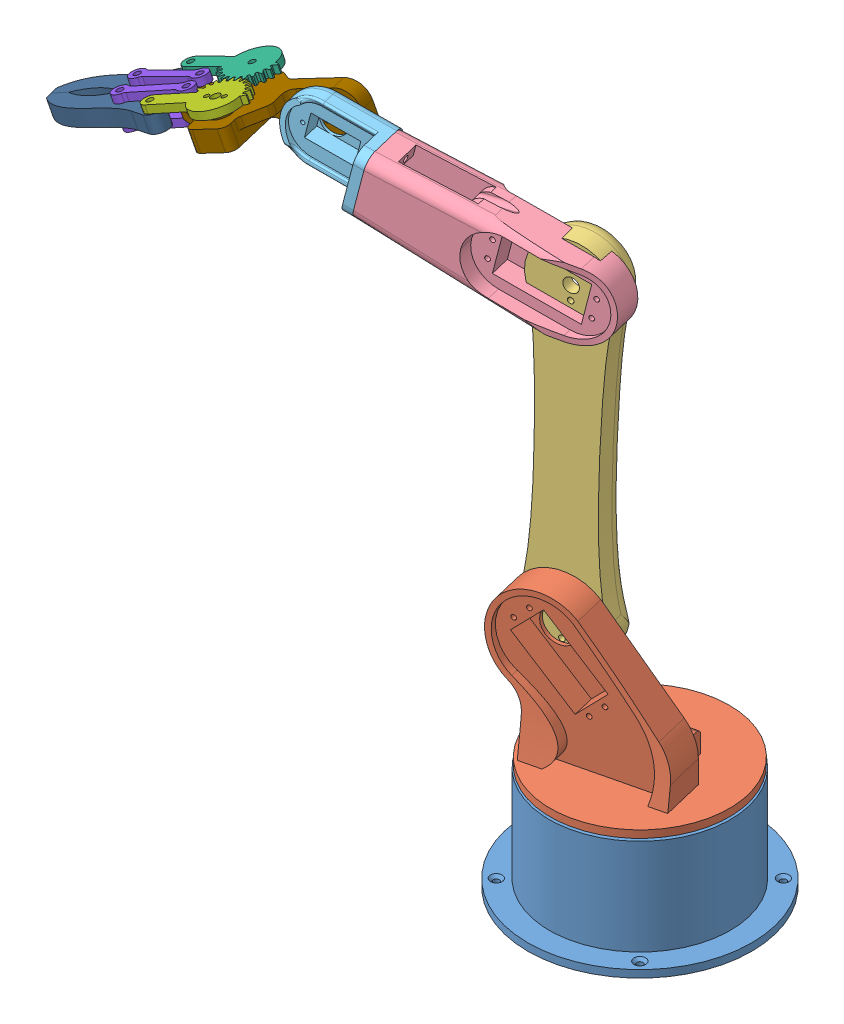
SolidWorks assembly Robotic Arm, configuration Default. Lengths in mm.
Overall size (333.86 325.62 149.88).
15 component instances, 10 part files, 15 mates.
Components (placement in the parent):
- Base-1: Base [Default] at (40.7793 36.1076 92.8796) size (121.25 56 121.25)
- Waist-1: Waist [Default] at (40.7793 93.1076 92.8796) x (-0.233849 0 -0.972273) z (0.972273 0 -0.233849) size (97 81.79 105.4)
- Arm 01-1: Arm 01 [Default] at (10.2173 150.3969 104.3443) x (-0.971972 0.024864 0.233776) z (-0.233849 0 -0.972273) size (58.02 214.69 21.06)
- Arm 02 v3-1: Arm 02 v3 [Default] at (-20.2557 318.087 105.5025) x (0.216544 0.974883 -0.052083) z (0.233849 0 0.972273) size (38.57 115 28.32)
- Arm 03-1: Arm 03 [Default] at (-71.2183 330.3365 122.9025) x (0.216544 0.974883 -0.052083) z (0.233849 0 0.972273) size (33 46 28)
- Gripper Assembly-2: Gripper Assembly [Default] at (-85.5006 347.4318 120.1943) x (0.233849 0 0.972273) z (-0.903375 -0.369736 0.217277) size (65.56 35.5 144.98)
  - gear1-1: gear1 [Default] at (-17.5467 12.6028 65.1565) x (-0.051418 0 0.998677) z (-0.998677 0 -0.051418) size (49.29 4 26.63)
  - gear2-1: gear2 [Default] at (10.7105 12.6028 44.992) x (0.082871 0 -0.99656) z (0.99656 0 0.082871) size (49.02 4 26.63)
  - grip link 1-1: grip link 1 [Default] at (-10.0646 0.1028 106.0462) x (0.033468 0 -0.99944) z (0.99944 0 0.033468) size (39 4 8)
  - Gripper base-1: Gripper base [Default] at (-22.027 4.1028 80.0636) size (44.4 28 77)
  - grip link 1-2: grip link 1 [Default] at (2.7155 0.1028 106.0146) x (-0.056211 0 -0.998419) z (0.998419 0 -0.056211) size (39 4 8)
  - Gripper 1-1: Gripper 1 [Default] at (8.7088 4.1028 79.2175) x (0 1 0) z (0.392312 0 -0.919832) size (8.5 22.22 65.31)
  - Gripper 1-2: Gripper 1 [Default] at (-15.9423 12.6028 79.2236) x (0 -1 0) z (-0.388345 0 -0.921514) size (8.5 22.22 65.31)
  - grip link 1-3: grip link 1 [Default] at (2.7155 12.6028 106.0146) x (-0.056211 0 -0.998419) z (0.998419 0 -0.056211) size (39 4 8)
  - grip link 1-4: grip link 1 [Default] at (-10.0646 16.6028 106.0462) x (0.033468 0 -0.99944) z (-0.99944 0 -0.033468) size (39 4 8)
Mates (geometry in assembly coordinates):
- Concentric5: concentric aligned: cylinder of Base-1 through (40.7793 92.1076 92.8796) axis (0 -1 0) radius 49; cylinder of Waist-1 through (40.7793 97.1076 92.8796) axis (0 -1 0) radius 48.5
- Distance1: distance = 1 mm anti-aligned: plane of Base-1 through (40.7793 92.1076 92.8796) normal (0 1 0); plane of Waist-1 through (40.7793 93.1076 92.8796) normal (0 -1 0)
- Parallel10: parallel anti-aligned: plane of Arm 02 v3-1 through (-72.3875 330.3365 118.0411) normal (-0.947852 0.222719 0.227975); plane of Arm 03-1 through (-71.2183 330.3365 122.9025) normal (0.947852 -0.222719 -0.227975)
- Parallel11: parallel aligned: line of Arm 02 v3-1 through (-71.986 340.5667 109.7164) axis (-0.216544 -0.974883 0.052083); line of Arm 03-1 through (-72.2185 340.5728 108.7438) axis (-0.216544 -0.974883 0.052083)
- Concentric21: concentric anti-aligned: cylinder of Arm 02 v3-1 through (-58.5912 341.7577 120.3797) axis (-0.947852 0.222719 0.227975) radius 1.5; cylinder of Arm 03-1 through (-111.6709 354.23 133.1463) axis (0.947852 -0.222719 -0.227975) radius 1.5
- Coincident57: coincident anti-aligned: plane of Arm 02 v3-1 through (-72.3875 330.3365 118.0411) normal (-0.947852 0.222719 0.227975); plane of Arm 03-1 through (-71.2183 330.3365 122.9025) normal (0.947852 -0.222719 -0.227975)
- Concentric24: concentric anti-aligned: cylinder of Arm 02 v3-1 through (-64.6545 314.461 121.838) axis (-0.947852 0.222719 0.227975) radius 1.5; cylinder of Arm 03-1 through (-117.7342 326.9333 134.6046) axis (0.947852 -0.222719 -0.227975) radius 1.5
- Coincident67: coincident anti-aligned: plane of Arm 03-1 through (-121.6663 324.4961 120.6369) normal (-0.233849 0 -0.972273); plane of Gripper Assembly-2/Gripper base-1 through (-126.8424 341.0767 121.8818) normal (0.233849 0 0.972273)
- Parallel15: parallel anti-aligned: plane of Arm 03-1 through (-121.6663 324.4961 120.6369) normal (-0.233849 0 -0.972273); plane of Gripper Assembly-2/Gripper base-1 through (-126.8424 341.0767 121.8818) normal (0.233849 0 0.972273)
- Parallel18: parallel anti-aligned: plane of Arm 03-1 through (-121.6663 324.4961 120.6369) normal (-0.233849 0 -0.972273); plane of Gripper Assembly-2/Gripper base-1 through (-126.8424 341.0767 121.8818) normal (0.233849 0 0.972273)
- Coincident68: coincident anti-aligned: plane of Waist-1 through (41.7146 93.1076 96.7687) normal (-0.233849 0 -0.972273); plane of Arm 01-1 through (10.2173 150.3969 104.3443) normal (0.233849 0 0.972273)
- Concentric25: concentric aligned: cylinder of Waist-1 through (20.6238 150.3969 147.6114) axis (-0.233849 0 -0.972273) radius 9; cylinder of Arm 01-1 through (10.2175 150.3969 104.3453) axis (-0.233849 0 -0.972273) radius 3.75
- Concentric26: concentric aligned: cylinder of Arm 01-1 through (14.0855 310.3475 103.415) axis (-0.233849 0 -0.972273) radius 3.75; circle of Arm 02 v3-1
- Coincident70: coincident anti-aligned: plane of Arm 01-1 through (12.6822 310.3475 97.5804) normal (-0.233849 0 -0.972273); plane of Arm 02 v3-1 through (18.6063 308.9555 96.1555) normal (0.233849 0 0.972273)
- Concentric27: concentric aligned: circle of Arm 03-1; cylinder of Gripper Assembly-2/Gripper base-1 through (-104.3059 336.5727 102.0621) axis (0.233849 0 0.972273) radius 2.5
